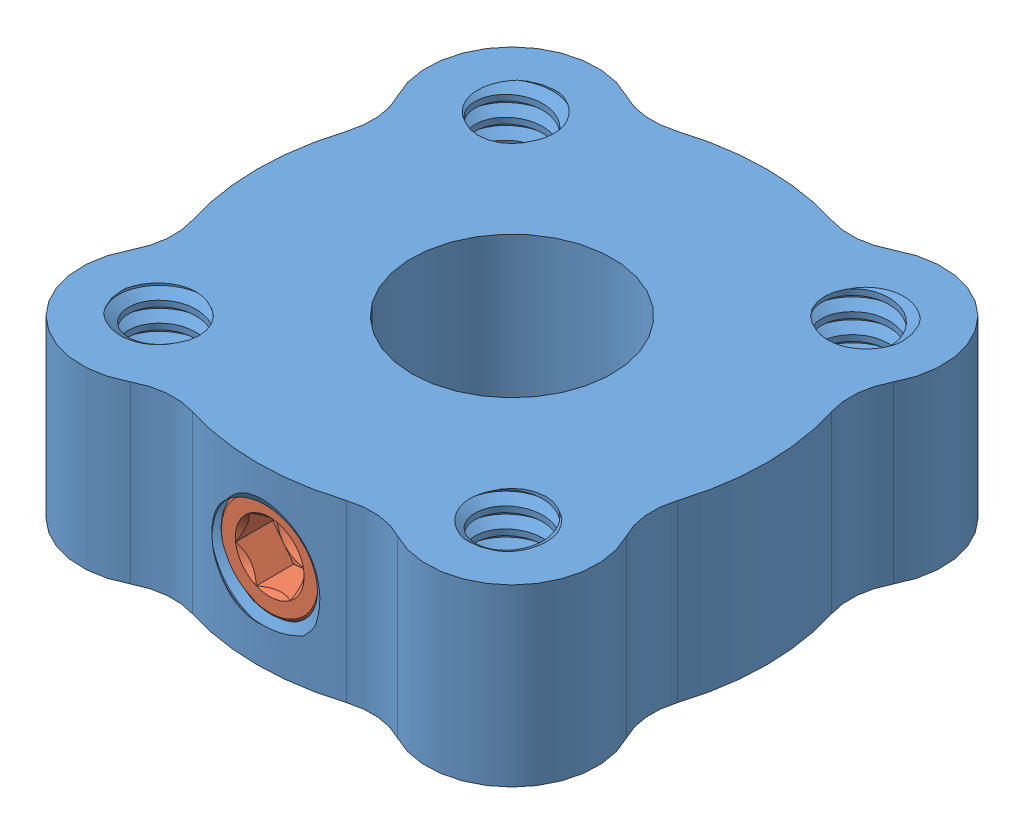
SolidWorks assembly 545636-8mm hub, configuration Default. Lengths in mm.
Overall size (20.57 9.52 20.57).
2 component instances, 2 part files, 0 mates.
Components (placement in the parent):
- 545636-1: 545636 [Default] at (-47.1957 16.7986 10.1368) size (20.57 9.53 20.57)
- 632138_91375A438-1: 632138_91375A438 [Default] at (-47.1957 22.8311 17.0285) x (0.920896 -0.389809 0) z (0 0 1) size (4.98 4.83 6.49)
